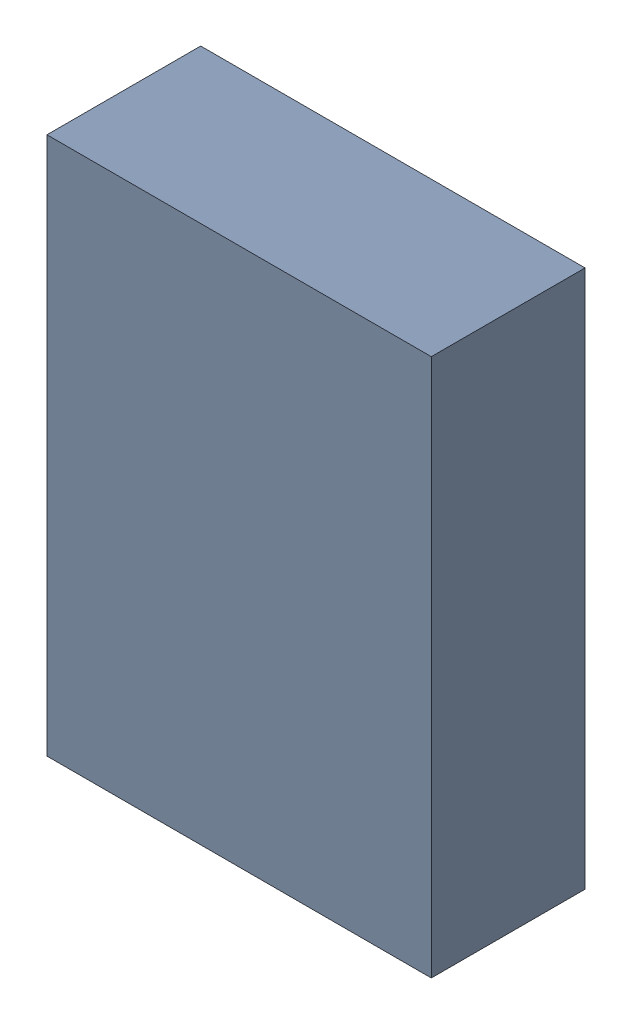
SolidWorks assembly Kanaloa_v2.0.0_Power_2, configuration Default. Lengths in mm.
Overall size (2.5 3.5 1).
2 component instances, 1 part files, 0 mates.
Components (placement in the parent):
- 378153280-1: 378153280 [Default] at (126.2166 87.376 0) size (2.5 3.5 1)
  - Extruded-1: Extruded [Default] at origin size (2.5 3.5 1)
